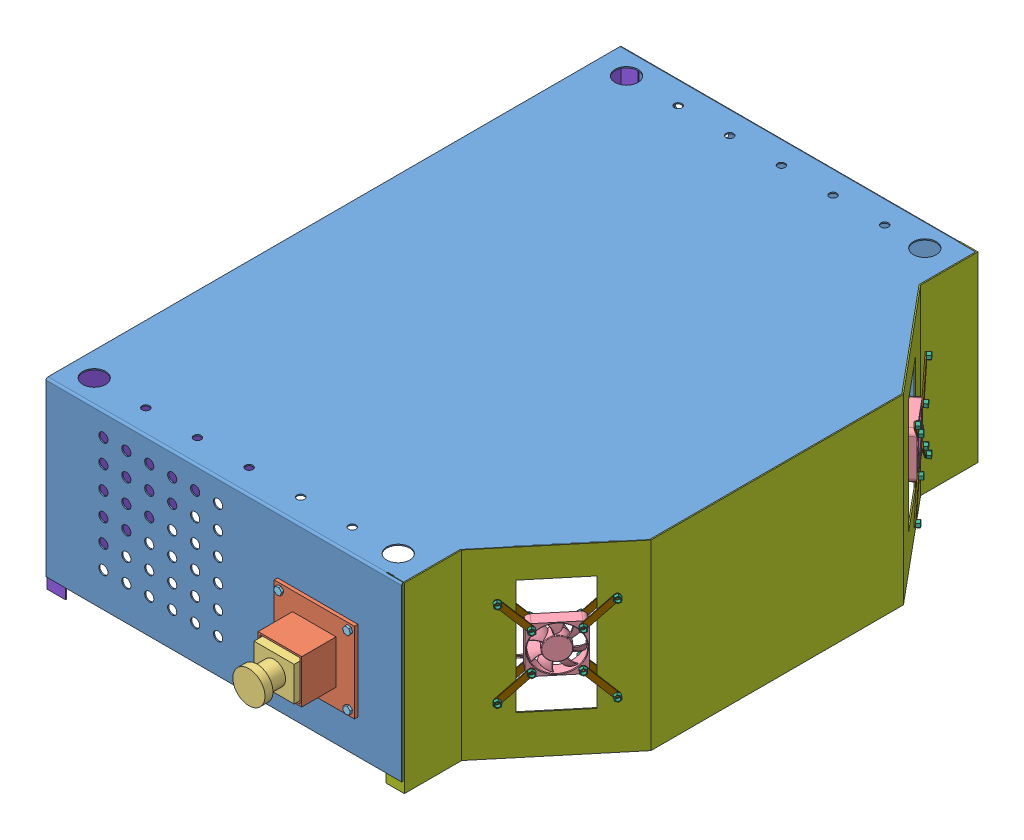
SolidWorks assembly My assembly, configuration Default. Lengths in mm.
Overall size (386 160 562).
63 component instances, 9 part files, 35 mates.
Components (placement in the parent):
- ushaped part-1: ushaped part [Default] at (-32.2459 -57.3253 -449.8573) size (385 150 502)
- 3d_printed_part_killswitch-2: 3d_printed_part_killswitch [Default] at (16.239 -142.3253 -176.118) x (-1 0 0) z (0 0 -1) size (70 70 33)
- kill_switch-2: kill_switch [Default] at (16.239 -157.3253 -158.618) x (0 0 -1) z (0 1 0) size (57 35 30)
- 40x40x10 DC Fan.step-2: 40x40x10 DC Fan.step [Default] at (127.5464 -132.3253 -275.8592) x (-0.640184 0 0.768221) z (-0.768221 0 -0.640184) size (49.86 40.69 10.5)
- 4mm_bolt-4: 4mm_bolt [Default] at (46.239 -172.3253 -174.118) x (0.78769 -0.616072 0) z (0 0 -1) size (6.92 6.14 22)
- nut_4mm-5: nut_4mm [Default] at (46.239 -172.3253 -183.118) x (-0.980343 0.197302 0) z (0 0 1) size (5.6 5.55 3)
- front_part-4: front_part [Default] at (165.3813 -216.3253 -430.48) x (1 0 0) z (0 1 0) size (91 500 159)
- back_part-3: back_part [Default] at (-220.1187 -217.3253 -430.118) x (-1 0 0) z (0 1 0) size (16 500 159)
- 4mm_bolt-5: 4mm_bolt [Default] at (-13.761 -172.3253 -174.118) x (-0.090924 0.995858 0) z (0 0 -1) size (6.92 6.14 22)
- 4mm_bolt-8: 4mm_bolt [Default] at (46.239 -112.3253 -174.118) x (-0.419673 0.907675 0) z (0 0 -1) size (6.92 6.14 22)
- 4mm_bolt-10: 4mm_bolt [Default] at (-13.761 -112.3253 -174.118) x (0.971864 0.235543 0) z (0 0 -1) size (6.92 6.14 22)
- nut_4mm-15: nut_4mm [Default] at (46.239 -112.3253 -183.118) x (0.696528 -0.717529 0) z (0 0 1) size (5.6 5.55 3)
- nut_4mm-17: nut_4mm [Default] at (-13.761 -172.3253 -183.118) x (0.631797 -0.775134 0) z (0 0 1) size (5.6 5.55 3)
- nut_4mm-19: nut_4mm [Default] at (-13.761 -112.3253 -183.118) x (-0.762958 -0.646448 0) z (0 0 1) size (5.6 5.55 3)
- Part1-1: Part1 [Default] at (136.3211 -105.7187 -303.1809) x (0.452679 -0.707107 -0.543214) z (0.768221 0 0.640184) size (5 35 1)
- nut_4mm-20: nut_4mm [Default] at (144.2637 -95.1121 -310.3689) x (0.393867 -0.78834 -0.47264) z (0.768221 0 0.640184) size (5.6 5.55 3)
- nut_4mm-21: nut_4mm [Default] at (130.6833 -116.3253 -294.0724) x (-0.179877 -0.959714 0.215853) z (0.768221 0 0.640184) size (5.6 5.55 3)
- nut_4mm-23: nut_4mm [Default] at (156.1711 -95.1121 -300.446) x (0.393867 -0.78834 -0.47264) z (0.768221 0 0.640184) size (5.6 5.55 3)
- nut_4mm-24: nut_4mm [Default] at (142.5907 -116.3253 -284.1496) x (-0.179877 -0.959714 0.215853) z (0.768221 0 0.640184) size (5.6 5.55 3)
- Part1-2: Part1 [Default] at (152.8379 -105.7187 -289.417) x (-0.452679 0.707107 0.543214) z (-0.768221 0 -0.640184) size (5 35 1)
- Part1-3: Part1 [Default] at (118.7716 -105.7187 -248.5374) x (-0.452679 -0.707107 0.543214) z (-0.768221 0 -0.640184) size (5 35 1)
- nut_4mm-26: nut_4mm [Default] at (124.4095 -116.3253 -257.6459) x (0.179877 -0.959714 -0.215853) z (-0.768221 0 -0.640184) size (5.6 5.55 3)
- nut_4mm-27: nut_4mm [Default] at (110.8291 -95.1121 -241.3495) x (-0.393867 -0.78834 0.47264) z (-0.768221 0 -0.640184) size (5.6 5.55 3)
- nut_4mm-28: nut_4mm [Default] at (98.9217 -95.1121 -251.2724) x (-0.393867 -0.78834 0.47264) z (-0.768221 0 -0.640184) size (5.6 5.55 3)
- Part1-4: Part1 [Default] at (102.2549 -105.7187 -262.3014) x (0.452679 0.707107 -0.543214) z (0.768221 0 0.640184) size (5 35 1)
- nut_4mm-29: nut_4mm [Default] at (112.5021 -116.3253 -267.5688) x (0.179877 -0.959714 -0.215853) z (-0.768221 0 -0.640184) size (5.6 5.55 3)
- Part1-5: Part1 [Default] at (152.8379 -158.9319 -289.417) x (0.452679 0.707107 -0.543214) z (-0.768221 0 -0.640184) size (5 35 1)
- nut_4mm-30: nut_4mm [Default] at (144.8954 -148.3253 -282.229) x (-0.179877 0.959714 0.215853) z (-0.768221 0 -0.640184) size (5.6 5.55 3)
- nut_4mm-31: nut_4mm [Default] at (158.4757 -169.5385 -298.5255) x (0.393867 0.78834 -0.47264) z (-0.768221 0 -0.640184) size (5.6 5.55 3)
- nut_4mm-32: nut_4mm [Default] at (146.5683 -169.5385 -308.4483) x (0.393867 0.78834 -0.47264) z (-0.768221 0 -0.640184) size (5.6 5.55 3)
- Part1-6: Part1 [Default] at (136.3211 -158.9319 -303.1809) x (0.452679 0.707107 -0.543214) z (0.768221 0 0.640184) size (5 35 1)
- nut_4mm-33: nut_4mm [Default] at (132.988 -148.3253 -292.1519) x (-0.179877 0.959714 0.215853) z (-0.768221 0 -0.640184) size (5.6 5.55 3)
- Part1-7: Part1 [Default] at (118.7716 -158.9319 -248.5374) x (0.452679 -0.707107 -0.543214) z (-0.768221 0 -0.640184) size (5 35 1)
- nut_4mm-34: nut_4mm [Default] at (122.1048 -148.3253 -259.5665) x (0.179877 0.959714 -0.215853) z (0.768221 0 0.640184) size (5.6 5.55 3)
- nut_4mm-35: nut_4mm [Default] at (108.5245 -169.5385 -243.2701) x (-0.393867 0.78834 0.47264) z (0.768221 0 0.640184) size (5.6 5.55 3)
- nut_4mm-36: nut_4mm [Default] at (96.617 -169.5385 -253.1929) x (-0.393867 0.78834 0.47264) z (0.768221 0 0.640184) size (5.6 5.55 3)
- Part1-8: Part1 [Default] at (102.2549 -158.9319 -262.3014) x (-0.452679 0.707107 0.543214) z (0.768221 0 0.640184) size (5 35 1)
- nut_4mm-37: nut_4mm [Default] at (110.1974 -148.3253 -269.4894) x (0.179877 0.959714 -0.215853) z (0.768221 0 0.640184) size (5.6 5.55 3)
- Part1-9: Part1 [Default] at (152.8379 -105.7187 -571.5431) x (0.452679 -0.707107 0.543214) z (-0.768221 0 0.640184) size (5 35 1)
- nut_4mm-38: nut_4mm [Default] at (144.8954 -116.3253 -578.7311) x (-0.179877 -0.959714 -0.215853) z (-0.768221 0 0.640184) size (5.6 5.55 3)
- nut_4mm-39: nut_4mm [Default] at (158.4757 -95.1121 -562.4346) x (0.393867 -0.78834 0.47264) z (-0.768221 0 0.640184) size (5.6 5.55 3)
- nut_4mm-40: nut_4mm [Default] at (146.5683 -95.1121 -552.5118) x (0.393867 -0.78834 0.47264) z (-0.768221 0 0.640184) size (5.6 5.55 3)
- Part1-10: Part1 [Default] at (136.3211 -105.7187 -557.7792) x (-0.452679 0.707107 -0.543214) z (0.768221 0 -0.640184) size (5 35 1)
- nut_4mm-41: nut_4mm [Default] at (132.988 -116.3253 -568.8082) x (-0.179877 -0.959714 -0.215853) z (-0.768221 0 0.640184) size (5.6 5.55 3)
- Part1-11: Part1 [Default] at (118.7716 -105.7187 -612.4226) x (0.452679 0.707107 0.543214) z (-0.768221 0 0.640184) size (5 35 1)
- nut_4mm-42: nut_4mm [Default] at (122.1048 -116.3253 -601.3936) x (0.179877 -0.959714 0.215853) z (0.768221 0 -0.640184) size (5.6 5.55 3)
- nut_4mm-43: nut_4mm [Default] at (108.5245 -95.1121 -617.69) x (-0.393867 -0.78834 -0.47264) z (0.768221 0 -0.640184) size (5.6 5.55 3)
- nut_4mm-44: nut_4mm [Default] at (96.617 -95.1121 -607.7672) x (-0.393867 -0.78834 -0.47264) z (0.768221 0 -0.640184) size (5.6 5.55 3)
- Part1-12: Part1 [Default] at (102.2549 -105.7187 -598.6587) x (-0.452679 -0.707107 -0.543214) z (0.768221 0 -0.640184) size (5 35 1)
- nut_4mm-45: nut_4mm [Default] at (110.1974 -116.3253 -591.4707) x (0.179877 -0.959714 0.215853) z (0.768221 0 -0.640184) size (5.6 5.55 3)
- Part1-13: Part1 [Default] at (152.8379 -158.9319 -571.5431) x (-0.452679 -0.707107 -0.543214) z (-0.768221 0 0.640184) size (5 35 1)
- nut_4mm-46: nut_4mm [Default] at (142.5907 -148.3253 -576.8105) x (-0.179877 0.959714 -0.215853) z (0.768221 0 -0.640184) size (5.6 5.55 3)
- nut_4mm-47: nut_4mm [Default] at (156.1711 -169.5385 -560.5141) x (0.393867 0.78834 0.47264) z (0.768221 0 -0.640184) size (5.6 5.55 3)
- nut_4mm-48: nut_4mm [Default] at (144.2637 -169.5385 -550.5912) x (0.393867 0.78834 0.47264) z (0.768221 0 -0.640184) size (5.6 5.55 3)
- Part1-14: Part1 [Default] at (136.3211 -158.9319 -557.7792) x (-0.452679 -0.707107 -0.543214) z (0.768221 0 -0.640184) size (5 35 1)
- nut_4mm-49: nut_4mm [Default] at (130.6833 -148.3253 -566.8876) x (-0.179877 0.959714 -0.215853) z (0.768221 0 -0.640184) size (5.6 5.55 3)
- Part1-15: Part1 [Default] at (118.7716 -158.9319 -612.4226) x (-0.452679 0.707107 -0.543214) z (-0.768221 0 0.640184) size (5 35 1)
- nut_4mm-50: nut_4mm [Default] at (124.4095 -148.3253 -603.3141) x (0.179877 0.959714 0.215853) z (-0.768221 0 0.640184) size (5.6 5.55 3)
- nut_4mm-51: nut_4mm [Default] at (110.8291 -169.5385 -619.6106) x (-0.393867 0.78834 -0.47264) z (-0.768221 0 0.640184) size (5.6 5.55 3)
- nut_4mm-52: nut_4mm [Default] at (98.9217 -169.5385 -609.6877) x (-0.393867 0.78834 -0.47264) z (-0.768221 0 0.640184) size (5.6 5.55 3)
- Part1-16: Part1 [Default] at (102.2549 -158.9319 -598.6587) x (0.452679 -0.707107 0.543214) z (0.768221 0 -0.640184) size (5 35 1)
- nut_4mm-53: nut_4mm [Default] at (112.5021 -148.3253 -593.3913) x (0.179877 0.959714 0.215853) z (-0.768221 0 0.640184) size (5.6 5.55 3)
- 40x40x10 DC Fan.step-3: 40x40x10 DC Fan.step [Default] at (127.5464 -132.3253 -585.1009) x (-0.640184 0 -0.768221) z (0.768221 0 -0.640184) size (49.86 40.69 10.5)
Mates (geometry in assembly coordinates):
- ProfileCenter1: profile center anti-aligned: plane of kill_switch-2 through (-1.261 -127.3253 -176.118) normal (0 0 -1); plane of 3d_printed_part_killswitch-2 through (16.239 -142.3253 -176.118) normal (0 0 1)
- Concentric1: concentric anti-aligned: cylinder of 3d_printed_part_killswitch-2 through (46.239 -172.3253 -175.118) axis (0 0 -1) radius 2; cylinder of 4mm_bolt-4 through (46.239 -172.3253 -196.118) axis (0 0 1) radius 2
- Coincident2: coincident anti-aligned: plane of 3d_printed_part_killswitch-2 through (16.239 -142.3253 -176.118) normal (0 0 1); plane of 4mm_bolt-4 through (46.239 -172.3253 -176.118) normal (0 0 -1)
- Concentric2: concentric anti-aligned: cylinder of 3d_printed_part_killswitch-2 through (-13.761 -172.3253 -175.118) axis (0 0 -1) radius 2; cylinder of 4mm_bolt-5 through (-13.761 -172.3253 -196.118) axis (0 0 1) radius 2
- Coincident3: coincident anti-aligned: plane of 3d_printed_part_killswitch-2 through (16.239 -142.3253 -176.118) normal (0 0 1); plane of 4mm_bolt-5 through (-13.761 -172.3253 -176.118) normal (0 0 -1)
- Concentric3: concentric anti-aligned: cylinder of 3d_printed_part_killswitch-2 through (46.239 -112.3253 -175.118) axis (0 0 -1) radius 2; cylinder of 4mm_bolt-8 through (46.239 -112.3253 -196.118) axis (0 0 1) radius 2
- Coincident4: coincident anti-aligned: plane of 3d_printed_part_killswitch-2 through (16.239 -142.3253 -176.118) normal (0 0 1); plane of 4mm_bolt-8 through (46.239 -112.3253 -176.118) normal (0 0 -1)
- Concentric4: concentric anti-aligned: cylinder of 3d_printed_part_killswitch-2 through (-13.761 -112.3253 -175.118) axis (0 0 -1) radius 2; cylinder of 4mm_bolt-10 through (-13.761 -112.3253 -196.118) axis (0 0 1) radius 2
- Coincident5: coincident anti-aligned: plane of 3d_printed_part_killswitch-2 through (16.239 -142.3253 -176.118) normal (0 0 1); plane of 4mm_bolt-10 through (-13.761 -112.3253 -176.118) normal (0 0 -1)
- Concentric5: concentric aligned: cylinder of ushaped part-1 through (46.239 -172.3253 -189.118) axis (0 0 1) radius 2; cylinder of 4mm_bolt-4 through (46.239 -172.3253 -196.118) axis (0 0 1) radius 2
- Concentric6: concentric aligned: cylinder of ushaped part-1 through (-13.761 -172.3253 -189.118) axis (0 0 1) radius 2; cylinder of 4mm_bolt-5 through (-13.761 -172.3253 -196.118) axis (0 0 1) radius 2
- Coincident6: coincident anti-aligned: plane of ushaped part-1 through (-32.2459 -57.3253 -179.118) normal (0 0 1); plane of 3d_printed_part_killswitch-2 through (16.239 -142.3253 -179.118) normal (0 0 -1)
- Concentric7: concentric anti-aligned: cylinder of 4mm_bolt-4 through (46.239 -172.3253 -196.118) axis (0 0 1) radius 2; cylinder of nut_4mm-5 through (46.239 -172.3253 -180.118) axis (0 0 -1) radius 2
- Coincident7: coincident anti-aligned: plane of ushaped part-1 through (-32.2459 -57.3253 -180.118) normal (0 0 -1); plane of nut_4mm-5 through (46.239 -172.3253 -180.118) normal (0 0 1)
- Concentric11: concentric anti-aligned: cylinder of 4mm_bolt-8 through (46.239 -112.3253 -196.118) axis (0 0 1) radius 2; cylinder of nut_4mm-15 through (46.239 -112.3253 -180.118) axis (0 0 -1) radius 2
- Coincident11: coincident anti-aligned: plane of ushaped part-1 through (-32.2459 -57.3253 -180.118) normal (0 0 -1); plane of nut_4mm-15 through (46.239 -112.3253 -180.118) normal (0 0 1)
- Concentric12: concentric anti-aligned: cylinder of 4mm_bolt-5 through (-13.761 -172.3253 -196.118) axis (0 0 1) radius 2; cylinder of nut_4mm-17 through (-13.761 -172.3253 -180.118) axis (0 0 -1) radius 2
- Coincident12: coincident anti-aligned: plane of ushaped part-1 through (-32.2459 -57.3253 -180.118) normal (0 0 -1); plane of nut_4mm-17 through (-13.761 -172.3253 -180.118) normal (0 0 1)
- Concentric13: concentric anti-aligned: cylinder of 4mm_bolt-10 through (-13.761 -112.3253 -196.118) axis (0 0 1) radius 2; cylinder of nut_4mm-19 through (-13.761 -112.3253 -180.118) axis (0 0 -1) radius 2
- Coincident13: coincident anti-aligned: plane of ushaped part-1 through (-32.2459 -57.3253 -180.118) normal (0 0 -1); plane of nut_4mm-19 through (-13.761 -112.3253 -180.118) normal (0 0 1)
- Coincident18: coincident anti-aligned: line of ushaped part-1 through (164.3813 -57.3253 -320.118) axis (0 0 -1); line of front_part-4 through (164.3813 -57.3253 -540.118) axis (0 0 1)
- Coincident19: coincident anti-aligned: line of ushaped part-1 through (164.3813 -58.3253 -540.118) axis (0 1 0); line of front_part-4 through (164.3813 -57.3253 -540.118) axis (0 -1 0)
- Width1: width anti-aligned: plane of front_part-4 through (21.0197 -82.3253 -397.1741) normal (0 -1 0); plane of front_part-4 through (21.0197 -182.3253 -397.1741) normal (0 1 0); plane of 40x40x10 DC Fan.step-2 through (133.7562 -112.3253 -291.5117) normal (0 1 0); plane of 40x40x10 DC Fan.step-2 through (133.7562 -152.3253 -291.5117) normal (0 -1 0)
- Width2: width anti-aligned: plane of front_part-4 through (21.0197 -82.3253 -397.1741) normal (-0.640184 0 0.768221); plane of front_part-4 through (-10.9895 -82.3253 -358.7631) normal (0.640184 0 -0.768221); plane of 40x40x10 DC Fan.step-2 through (136.3169 -116.3253 -294.5846) normal (0.640184 0 -0.768221); plane of 40x40x10 DC Fan.step-2 through (110.7095 -116.3253 -263.8557) normal (-0.640184 0 0.768221)
- Width3: width anti-aligned: plane of front_part-4 through (90.3813 -57.3253 -230.48) normal (0.768221 0 0.640184); plane of front_part-4 through (89.3813 -57.3253 -230.8421) normal (-0.768221 0 -0.640184); plane of 40x40x10 DC Fan.step-2 through (123.5132 -132.3253 -279.2202) normal (-0.768221 0 -0.640184); plane of 40x40x10 DC Fan.step-2 through (141.8225 -148.3253 -284.7898) normal (0.768221 0 0.640184)
- Concentric14: concentric aligned: cylinder of 40x40x10 DC Fan.step-2 through (133.7562 -116.3253 -291.5117) axis (-0.768221 0 -0.640184) radius 1.725; cylinder of Part1-1 through (133.7562 -116.3253 -291.5117) axis (-0.768221 0 -0.640184) radius 2
- Coincident20: coincident anti-aligned: plane of 40x40x10 DC Fan.step-2 through (123.5132 -132.3253 -279.2202) normal (-0.768221 0 -0.640184); plane of Part1-1 through (133.7562 -116.3253 -291.5117) normal (0.768221 0 0.640184)
- Coincident22: coincident anti-aligned: plane of Part1-1 through (132.988 -116.3253 -292.1519) normal (-0.768221 0 -0.640184); plane of nut_4mm-20 through (146.5683 -95.1121 -308.4483) normal (0.768221 0 0.640184)
- Angle1: planar angle = 2.356194 rad anti-aligned: plane of Part1-1 through (132.6245 -114.5576 -290.1537) normal (-0.452679 0.707107 0.543214); plane of 40x40x10 DC Fan.step-2 through (133.7562 -112.3253 -291.5117) normal (0 1 0)
- Coincident24: coincident anti-aligned: plane of Part1-1 through (132.988 -116.3253 -292.1519) normal (-0.768221 0 -0.640184); plane of nut_4mm-21 through (132.988 -116.3253 -292.1519) normal (0.768221 0 0.640184)
- Coincident28: coincident anti-aligned: plane of ushaped part-1 through (-32.2459 -58.3253 -449.8573) normal (0 -1 0); plane of back_part-3 through (-220.1187 -58.3253 -430.118) normal (0 1 0)
- Coincident29: coincident anti-aligned: plane of ushaped part-1 through (-32.2459 -57.3253 -180.118) normal (0 0 -1); plane of back_part-3 through (-220.6187 -58.3253 -180.118) normal (0 0 1)
- Coincident30: coincident aligned: plane of ushaped part-1 through (-220.6187 -207.3253 -681.118) normal (-1 0 0); plane of back_part-3 through (-220.6187 -58.3253 -181.118) normal (-1 0 0)
- Concentric15: concentric aligned: cylinder of Part1-3 through (107.7562 -95.1121 -243.9102) axis (0.768221 0 0.640184) radius 2; cylinder of nut_4mm-27 through (108.5245 -95.1121 -243.2701) axis (0.768221 0 0.640184) radius 2
- Concentric16: concentric aligned: cylinder of Part1-3 through (121.3366 -116.3253 -260.2067) axis (0.768221 0 0.640184) radius 2; cylinder of nut_4mm-26 through (122.1048 -116.3253 -259.5665) axis (0.768221 0 0.640184) radius 2
